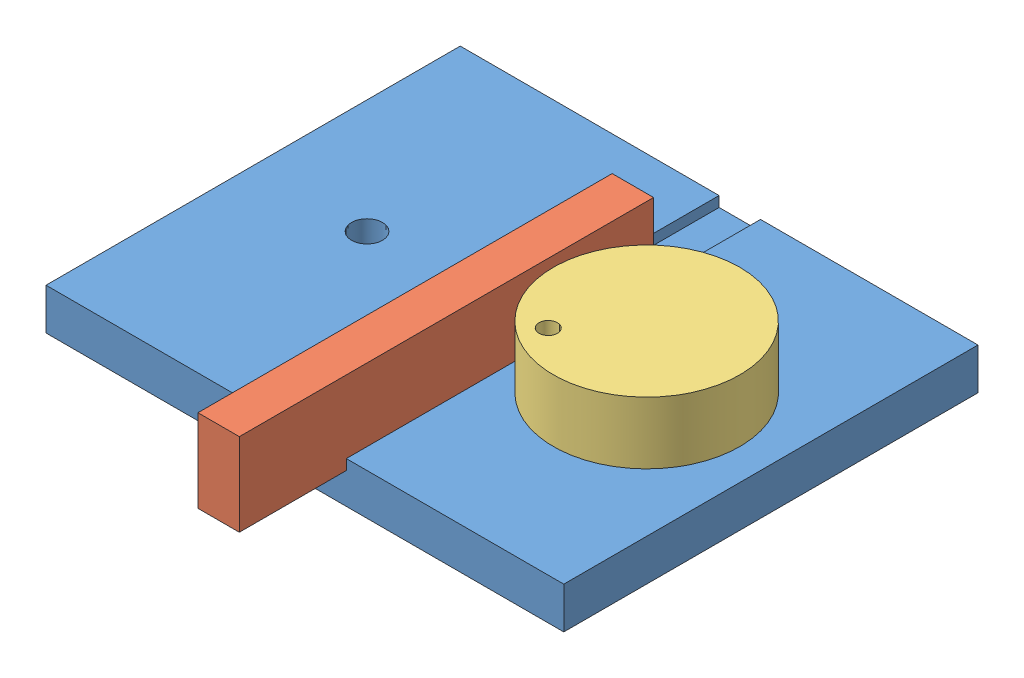
SolidWorks assembly ans cu cremaliera, configuration Default. Lengths in mm.
Overall size (50.24 11 50.33).
3 component instances, 3 part files, 5 mates.
Components (placement in the parent):
- baza1-1: baza1 [Default] at (-3.6711 -0.3362 -19.1932) size (50 4 40)
- cremaliera-1: cremaliera [Default] at (7.4085 4.9414 -8.8638) size (4 8 40)
- roata mica-1: roata mica [Default] at (9.3289 9.6638 0.8068) x (0.874514 0 0.485) z (0 -1 0) size (18 18 6)
Mates (geometry in assembly coordinates):
- Coincident1: coincident anti-aligned: plane of baza1-1 through (-3.6711 2.6638 -19.1932) normal (0 1 0); plane of cremaliera-1 through (-3.6711 2.6638 31.1362) normal (0 -1 0)
- Coincident2: coincident anti-aligned: plane of baza1-1 through (0.3289 4.6765 -19.1932) normal (-1 0 0); plane of cremaliera-1 through (0.3289 10.6638 31.1362) normal (1 0 0)
- Coincident3: coincident anti-aligned: plane of baza1-1 through (-28.6711 3.6638 -19.1932) normal (0 1 0); plane of roata mica-1 through (9.3289 3.6638 0.8068) normal (0 -1 0)
- Concentric1: concentric anti-aligned: cylinder of baza1-1 through (9.3289 63.8199 0.8068) axis (0 -1 0) radius 1.5; cylinder of roata mica-1 through (9.3289 3.6638 0.8068) axis (0 1 0) radius 9
- RackPinionMate1: rack pinion = 18 mm: line of cremaliera-1 through (0.3289 10.6638 31.1362) axis (0 0 -1); cylinder of roata mica-1 through (9.3289 3.6638 0.8068) axis (0 1 0) radius 9
